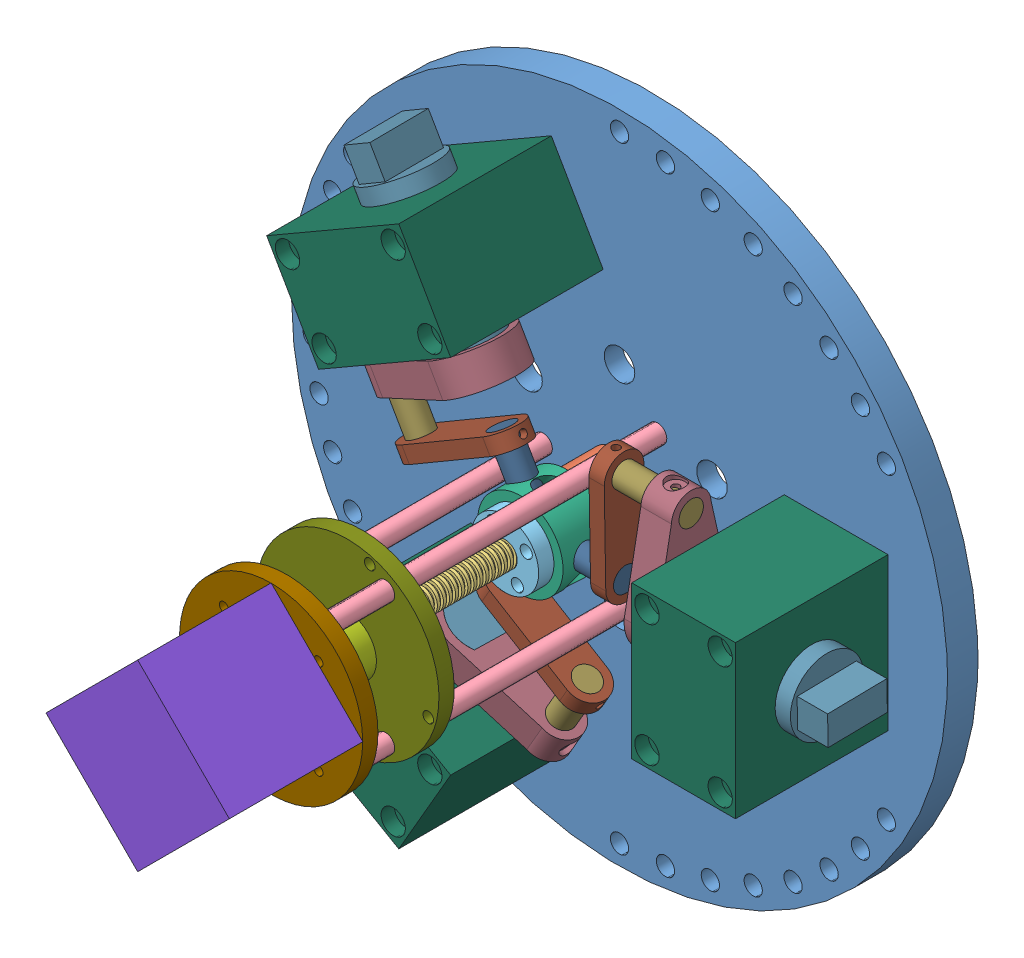
SolidWorks assembly Assem1, configuration Default. Lengths in mm.
Overall size (215 215 167.93).
30 component instances, 16 part files, 77 mates.
Components (placement in the parent):
- final base-1: final base [Default] at (64.558 110.2786 169.6179) size (215 215 10)
- lead screw holder-1: lead screw holder [Default] at (64.558 110.2786 179.6179) size (22 22 15)
- lead screw-1: lead screw [Default] at (64.558 110.2786 173.9381) x (0.932738 -0.360554 0) z (0 0 1) size (8 9.24 103.2)
- motor support-1: motor support [Default] at (77.058 131.9292 179.6179) size (6 6 110)
- main nut-1: main nut [Default] at (64.558 110.2786 217.1179) x (-0.5 0.866025 0) z (0 0 -1) size (22 22 17.19)
- main nut gasket-1: main nut gasket [Default] at (64.558 110.2786 197.1179) x (0.5 -0.866025 0) z (0 0 1) size (28 28 15)
- coupler-1: coupler [Default] at (64.558 110.2786 288.9381) x (0.864359 0.502875 0) z (0 0 -1) size (19 19 25)
- motor block-1: motor block [Default] at (64.558 110.2786 337.5481) x (0.707107 -0.707107 0) z (0 0 -1) size (42.5 42.5 58.61)
- motor holder-1: motor holder [Default] at (64.558 110.2786 293.7981) x (-1 0 0) z (0 0 -1) size (60 60 5)
- pin2-1: pin2 [Default] at (61.058 116.3407 204.6179) x (-0.865226 -0.499538 0.042959) z (-0.5 0.866025 0) size (8 8 20)
- cranck-1: cranck [Default] at (38.0694 126.1623 204.8677) x (0.865905 0.499931 -0.016654) z (0.5 -0.866025 0) size (43 13 5)
- pin-1: pin [Default] at (27.5808 114.3332 205.1175) x (-0.107928 -0.062312 0.992204) z (-0.5 0.866025 0) size (8 8 27)
- rotor-1: rotor [Default] at (27.0694 145.2149 204.8677) x (-0.865905 -0.499931 0.016654) z (0.5 -0.866025 0) size (49 25 10)
- shaft-1: shaft [Default] at (20.558 186.4888 204.6179) x (0.014423 0.008327 0.999861) z (0.5 -0.866025 0) size (24 24 64)
- shaft bracket-1: shaft bracket [Default] at (20.558 186.4888 204.6179) x (0.866025 0.5 0) z (0.5 -0.866025 0) size (50 50 34)
- motor support-4: motor support [Default] at (39.558 110.2786 179.6179) size (6 6 110)
- motor support-5: motor support [Default] at (77.058 88.6279 179.6179) size (6 6 110)
- pin2-4: pin2 [Default] at (61.058 104.2164 204.6179) x (-0.766894 0.442767 0.464576) z (-0.5 -0.866025 0) size (8 8 20)
- pin2-5: pin2 [Default] at (71.558 110.2786 204.6179) x (0 0 -1) z (1 0 0) size (8 8 20)
- cranck-4: cranck [Default] at (64.0465 79.3969 204.8677) x (0.865905 -0.499931 0.016654) z (0.5 0.866025 0) size (43 13 5)
- cranck-5: cranck [Default] at (91.558 125.2765 204.8677) x (0 0.999861 0.016654) z (-1 0 0) size (43 13 5)
- pin-4: pin [Default] at (86.558 140.2744 205.1175) x (0 0 -1) z (1 0 0) size (8 8 27)
- pin-5: pin [Default] at (79.5351 76.2281 205.1175) x (0.75 -0.433013 0.5) z (-0.5 -0.866025 0) size (8 8 27)
- rotor-4: rotor [Default] at (53.0465 60.3444 204.8677) x (0.865905 -0.499931 0.016654) z (0.5 0.866025 0) size (49 25 10)
- rotor-5: rotor [Default] at (113.558 125.2765 204.8677) x (0 0.999861 0.016654) z (-1 0 0) size (49 25 10)
- shaft-4: shaft [Default] at (152.558 110.2786 204.6179) x (0 -0.016654 0.999861) z (-1 0 0) size (24 24 64)
- shaft-5: shaft [Default] at (20.558 34.0683 204.6179) x (-0.014423 0.008327 0.999861) z (0.5 0.866025 0) size (24 24 64)
- shaft bracket-4: shaft bracket [Default] at (37.558 63.5132 204.6179) x (0.866025 -0.5 0) z (-0.5 -0.866025 0) size (50 50 34)
- shaft bracket-5: shaft bracket [Default] at (152.558 110.2786 204.6179) x (0 -1 0) z (-1 0 0) size (50 50 34)
- motor holder1-1: motor holder1 [Default] at (64.558 110.2786 263.7981) x (0.963841 -0.266478 0) z (0 0 1) size (60 60 5)
Mates (geometry in assembly coordinates):
- Coincident1: coincident: line of assembly; line of assembly; axis of final base-1 through (64.558 110.2786 179.6179) axis (0 0 -1); axis of lead screw holder-1 through (64.558 110.2786 194.6179) axis (0 0 -1)
- Coincident2: coincident: line of assembly; line of assembly; axis of final base-1 through (64.558 118.2786 175.6179) axis (0 0 1); axis of lead screw holder-1 through (64.558 118.2786 184.6179) axis (0 0 -1)
- Coincident3: coincident: line of assembly; line of assembly; axis of final base-1 through (64.558 102.2786 175.6179) axis (0 0 1); axis of lead screw holder-1 through (64.558 102.2786 184.6179) axis (0 0 -1)
- Coincident4: coincident: plane of final base-1 through (64.558 110.2786 179.6179) normal (0 0 1); plane of lead screw holder-1 through (64.558 110.2786 179.6179) normal (0 0 -1)
- Coincident5: coincident: line of assembly; line of assembly; axis of lead screw holder-1 through (64.558 110.2786 194.6179) axis (0 0 -1); axis of lead screw-1 through (64.558 110.2786 289.7579) axis (0 0 -1)
- Coincident6: coincident anti-aligned: line of final base-1 through (77.058 131.9292 173.6179) axis (0 0 1); line of motor support-1 through (77.058 131.9292 289.6179) axis (0 0 -1)
- Coincident7: coincident anti-aligned: plane of final base-1 through (64.558 110.2786 179.6179) normal (0 0 1); plane of motor support-1 through (77.058 131.9292 179.6179) normal (0 0 -1)
- Coincident8: coincident aligned: line of lead screw-1 through (64.558 110.2786 273.9381) axis (0 0 -1); line of main nut-1 through (64.558 110.2786 217.1179) axis (0 0 -1)
- RackPinionMate1: rack pinion = 0.6366 mm: cylinder of main nut-1 through (64.558 110.2786 202.1179) axis (0 0 1) radius 5.1; cylinder of lead screw-1 through (64.558 110.2786 273.9381) axis (0 0 -1) radius 4
- Coincident9: coincident aligned: line of lead screw-1 through (64.558 110.2786 273.9381) axis (0 0 -1); line of main nut gasket-1 through (64.558 110.2786 212.1179) axis (0 0 -1)
- Coincident10: coincident anti-aligned: line of main nut-1 through (60.558 117.2068 217.1179) axis (0 0 -1); line of main nut gasket-1 through (60.558 117.2068 205.6179) axis (0 0 1)
- Coincident11: coincident anti-aligned: line of main nut-1 through (57.6298 106.2786 217.1179) axis (0 0 -1); line of main nut gasket-1 through (57.6298 106.2786 205.6179) axis (0 0 1)
- Coincident12: coincident anti-aligned: plane of main nut-1 through (64.558 110.2786 212.1179) normal (0 0 -1); plane of main nut gasket-1 through (64.558 110.2786 212.1179) normal (0 0 1)
- Coincident13: coincident anti-aligned: line of lead screw-1 through (64.558 110.2786 273.9381) axis (0 0 -1); line of coupler-1 through (64.558 110.2786 263.9381) axis (0 0 1)
- Coincident14: coincident anti-aligned: plane of lead screw-1 through (64.558 110.2786 273.9381) normal (0 0 1); plane of coupler-1 through (64.558 110.2786 273.9381) normal (0 0 -1)
- Coincident15: coincident aligned: line of coupler-1 through (64.558 110.2786 263.9381) axis (0 0 1); line of motor block-1 through (64.558 110.2786 278.9381) axis (0 0 1)
- Coincident16: coincident anti-aligned: plane of coupler-1 through (64.558 110.2786 278.9381) normal (0 0 1); plane of motor block-1 through (64.558 110.2786 278.9381) normal (0 0 -1)
- Coincident17: coincident: line of coupler-1 through (64.558 110.2786 263.9381) axis (0 0 1); line of motor block-1 through (64.558 110.2786 304.6179) axis (0 0 1)
- Coincident18: coincident: line of assembly; line of assembly; axis of motor support-4 through (39.558 110.2786 289.6179) axis (0 0 -1); axis of motor holder-1 through (39.558 110.2786 309.6179) axis (0 0 -1)
- Coincident19: coincident: line of assembly; line of assembly; axis of motor support-1 through (77.058 131.9292 289.6179) axis (0 0 -1); axis of motor holder-1 through (77.058 131.9292 309.6179) axis (0 0 -1)
- Coincident21: coincident: plane of motor support-1 through (77.058 131.9292 289.6179) normal (0 0 1); plane of motor holder-1 through (64.558 110.2786 304.6179) normal (0 0 -1)
- Coincident22: coincident: plane of motor block-1 through (64.558 110.2786 293.7981) normal (0 0 -1); plane of motor holder-1 through (64.558 110.2786 309.6179) normal (0 0 1)
- Coincident23: coincident: line of assembly; line of assembly; axis of main nut gasket-1 through (61.058 116.3407 204.6179) axis (-0.5 0.866025 0); axis of pin2-1 through (51.058 133.6613 204.6179) axis (0.5 -0.866025 0)
- Coincident24: coincident: plane of main nut gasket-1 through (61.058 116.3407 204.6179) normal (-0.5 0.866025 0); plane of pin2-1 through (61.058 116.3407 204.6179) normal (0.5 -0.866025 0)
- Coincident25: coincident anti-aligned: line of pin2-1 through (51.058 133.6613 204.6179) axis (0.5 -0.866025 0); line of cranck-1 through (53.558 129.3311 204.6179) axis (-0.5 0.866025 0)
- Coincident27: coincident aligned: plane of pin2-1 through (51.058 133.6613 204.6179) normal (-0.5 0.866025 0); plane of cranck-1 through (25.0808 118.6633 205.1175) normal (-0.5 0.866025 0)
- Coincident28: coincident anti-aligned: line of cranck-1 through (27.5808 114.3332 205.1175) axis (-0.5 0.866025 0); line of pin-1 through (14.0808 137.7159 205.1175) axis (0.5 -0.866025 0)
- Coincident29: coincident aligned: plane of cranck-1 through (27.5808 114.3332 205.1175) normal (0.5 -0.866025 0); plane of pin-1 through (27.5808 114.3332 205.1175) normal (0.5 -0.866025 0)
- Coincident30: coincident anti-aligned: line of pin-1 through (14.0808 137.7159 205.1175) axis (0.5 -0.866025 0); line of rotor-1 through (19.0808 129.0556 205.1175) axis (-0.5 0.866025 0)
- Coincident31: coincident aligned: plane of pin-1 through (14.0808 137.7159 205.1175) normal (-0.5 0.866025 0); plane of rotor-1 through (14.0808 137.7159 205.1175) normal (-0.5 0.866025 0)
- Coincident32: coincident aligned: line of rotor-1 through (45.058 144.0536 204.6179) axis (-0.5 0.866025 0); line of shaft-1 through (45.058 144.0536 204.6179) axis (-0.5 0.866025 0)
- Coincident33: coincident anti-aligned: plane of rotor-1 through (39.9779 141.1206 212.7167) normal (0.865905 0.499931 -0.016654); plane of shaft-1 through (34.8625 149.7142 204.7178) normal (-0.865905 -0.499931 0.016654)
- Coincident34: coincident aligned: plane of rotor-1 through (19.0808 129.0556 205.1175) normal (0.5 -0.866025 0); plane of shaft-1 through (45.058 144.0536 204.6179) normal (0.5 -0.866025 0)
- Coincident35: coincident aligned: line of final base-1 through (40.3785 192.1587 169.6179) axis (0 0 1); line of shaft bracket-1 through (40.3785 192.1587 179.6179) axis (0 0 1)
- Coincident36: coincident aligned: line of final base-1 through (52.3785 171.3741 169.6179) axis (0 0 1); line of shaft bracket-1 through (52.3785 171.3741 179.6179) axis (0 0 1)
- Coincident37: coincident anti-aligned: plane of final base-1 through (64.558 110.2786 179.6179) normal (0 0 1); plane of shaft bracket-1 through (15.9073 144.5439 179.6179) normal (0 0 -1)
- Coincident38: coincident anti-aligned: line of shaft-1 through (45.058 144.0536 204.6179) axis (-0.5 0.866025 0); line of shaft bracket-1 through (20.558 186.4888 204.6179) axis (0.5 -0.866025 0)
- LimitDistance2: limit distance = 17.5 mm anti-aligned: plane of main nut gasket-1 through (64.558 110.2786 197.1179) normal (0 0 -1); plane of final base-1 through (64.558 110.2786 179.6179) normal (0 0 1)
- Coincident66: coincident anti-aligned: line of final base-1 through (39.558 110.2786 173.6179) axis (0 0 1); line of motor support-4 through (39.558 110.2786 289.6179) axis (0 0 -1)
- Coincident69: coincident anti-aligned: line of final base-1 through (77.058 88.6279 173.6179) axis (0 0 1); line of motor support-5 through (77.058 88.6279 289.6179) axis (0 0 -1)
- Coincident70: coincident anti-aligned: plane of final base-1 through (64.558 110.2786 179.6179) normal (0 0 1); plane of motor support-5 through (77.058 88.6279 179.6179) normal (0 0 -1)
- Coincident71: coincident: line of assembly; line of assembly; axis of main nut gasket-1 through (61.058 104.2164 204.6179) axis (-0.5 -0.866025 0); axis of pin2-4 through (51.058 86.8959 204.6179) axis (0.5 0.866025 0)
- Coincident72: coincident: plane of main nut gasket-1 through (61.058 104.2164 204.6179) normal (-0.5 -0.866025 0); plane of pin2-4 through (61.058 104.2164 204.6179) normal (0.5 0.866025 0)
- Coincident73: coincident: line of assembly; line of assembly; axis of main nut gasket-1 through (71.558 110.2786 204.6179) axis (1 0 0); axis of pin2-5 through (91.558 110.2786 204.6179) axis (-1 0 0)
- Coincident74: coincident: plane of main nut gasket-1 through (71.558 110.2786 204.6179) normal (1 0 0); plane of pin2-5 through (71.558 110.2786 204.6179) normal (-1 0 0)
- Coincident75: coincident anti-aligned: line of pin2-4 through (51.058 86.8959 204.6179) axis (0.5 0.866025 0); line of cranck-4 through (53.558 91.226 204.6179) axis (-0.5 -0.866025 0)
- Coincident76: coincident aligned: plane of pin2-4 through (51.058 86.8959 204.6179) normal (-0.5 -0.866025 0); plane of cranck-4 through (51.058 86.8959 204.6179) normal (-0.5 -0.866025 0)
- Coincident77: coincident anti-aligned: line of pin2-5 through (91.558 110.2786 204.6179) axis (-1 0 0); line of cranck-5 through (86.558 110.2786 204.6179) axis (1 0 0)
- Coincident78: coincident aligned: plane of pin2-5 through (91.558 110.2786 204.6179) normal (1 0 0); plane of cranck-5 through (91.558 110.2786 204.6179) normal (1 0 0)
- Coincident79: coincident anti-aligned: line of cranck-5 through (86.558 140.2744 205.1175) axis (1 0 0); line of pin-4 through (113.558 140.2744 205.1175) axis (-1 0 0)
- Coincident80: coincident aligned: plane of cranck-5 through (86.558 110.2786 204.6179) normal (-1 0 0); plane of pin-4 through (86.558 140.2744 205.1175) normal (-1 0 0)
- Coincident81: coincident anti-aligned: line of cranck-4 through (79.5351 76.2281 205.1175) axis (-0.5 -0.866025 0); line of pin-5 through (66.0351 52.8454 205.1175) axis (0.5 0.866025 0)
- Coincident82: coincident aligned: plane of cranck-4 through (53.558 91.226 204.6179) normal (0.5 0.866025 0); plane of pin-5 through (79.5351 76.2281 205.1175) normal (0.5 0.866025 0)
- Coincident83: coincident anti-aligned: line of pin-5 through (66.0351 52.8454 205.1175) axis (0.5 0.866025 0); line of rotor-4 through (71.0351 61.5057 205.1175) axis (-0.5 -0.866025 0)
- Coincident84: coincident aligned: plane of pin-5 through (66.0351 52.8454 205.1175) normal (-0.5 -0.866025 0); plane of rotor-4 through (66.0351 52.8454 205.1175) normal (-0.5 -0.866025 0)
- Coincident85: coincident anti-aligned: line of pin-4 through (113.558 140.2744 205.1175) axis (-1 0 0); line of rotor-5 through (103.558 140.2744 205.1175) axis (1 0 0)
- Coincident86: coincident aligned: plane of pin-4 through (113.558 140.2744 205.1175) normal (1 0 0); plane of rotor-5 through (113.558 140.2744 205.1175) normal (1 0 0)
- Coincident87: coincident aligned: line of rotor-4 through (45.058 76.5036 204.6179) axis (-0.5 -0.866025 0); line of shaft-5 through (45.058 76.5036 204.6179) axis (-0.5 -0.866025 0)
- Coincident88: coincident anti-aligned: plane of rotor-4 through (50.138 73.5706 212.7167) normal (-0.865905 0.499931 -0.016654); plane of shaft-5 through (45.2534 64.8437 204.7178) normal (0.865905 -0.499931 0.016654)
- Coincident89: coincident aligned: plane of rotor-4 through (71.0351 61.5057 205.1175) normal (0.5 0.866025 0); plane of shaft-5 through (45.058 76.5036 204.6179) normal (0.5 0.866025 0)
- Coincident90: coincident aligned: line of rotor-5 through (103.558 110.2786 204.6179) axis (1 0 0); line of shaft-4 through (103.558 110.2786 204.6179) axis (1 0 0)
- Coincident91: coincident anti-aligned: plane of rotor-5 through (103.558 116.1445 212.7167) normal (0 -0.999861 -0.016654); plane of shaft-4 through (113.558 116.2777 204.7178) normal (0 0.999861 0.016654)
- Coincident92: coincident aligned: plane of rotor-5 through (103.558 140.2744 205.1175) normal (-1 0 0); plane of shaft-4 through (103.558 110.2786 204.6179) normal (-1 0 0)
- Coincident93: coincident aligned: line of final base-1 through (147.558 90.2786 169.6179) axis (0 0 1); line of shaft bracket-5 through (147.558 90.2786 179.6179) axis (0 0 1)
- Coincident94: coincident aligned: line of final base-1 through (147.558 130.2786 169.6179) axis (0 0 1); line of shaft bracket-5 through (147.558 130.2786 179.6179) axis (0 0 1)
- Coincident95: coincident anti-aligned: plane of final base-1 through (64.558 110.2786 179.6179) normal (0 0 1); plane of shaft bracket-5 through (118.558 135.2786 179.6179) normal (0 0 -1)
- Coincident96: coincident anti-aligned: line of shaft-4 through (103.558 110.2786 204.6179) axis (1 0 0); line of shaft bracket-5 through (152.558 110.2786 204.6179) axis (-1 0 0)
- Coincident98: coincident aligned: line of final base-1 through (40.3785 28.3985 169.6179) axis (0 0 1); line of shaft bracket-4 through (40.3785 28.3985 179.6179) axis (0 0 1)
- Coincident99: coincident aligned: line of final base-1 through (52.3785 49.1831 169.6179) axis (0 0 1); line of shaft bracket-4 through (52.3785 49.1831 179.6179) axis (0 0 1)
- Coincident100: coincident anti-aligned: plane of final base-1 through (64.558 110.2786 179.6179) normal (0 0 1); plane of shaft bracket-4 through (-1.0927 46.5683 179.6179) normal (0 0 -1)
- Coincident101: coincident aligned: line of shaft-5 through (45.058 76.5036 204.6179) axis (-0.5 -0.866025 0); line of shaft bracket-4 through (37.558 63.5132 204.6179) axis (-0.5 -0.866025 0)
- Coincident102: coincident: line of assembly; line of assembly; axis of motor holder-1 through (39.558 110.2786 309.6179) axis (0 0 -1); axis of motor support-4 through (39.558 110.2786 304.6179) axis (0 0 -1)
- Coincident103: coincident: line of assembly; line of assembly; axis of motor block-1 through (64.558 88.3653 298.7981) axis (0 0 -1); axis of motor holder-1 through (64.558 88.3653 309.6179) axis (0 0 -1)
- Coincident106: coincident aligned: line of motor support-5 through (77.058 88.6279 289.6179) axis (0 0 -1); line of motor holder1-1 through (77.058 88.6279 268.7981) axis (0 0 -1)
- Coincident107: coincident aligned: line of motor support-4 through (39.558 110.2786 289.6179) axis (0 0 -1); line of motor holder1-1 through (39.558 110.2786 268.7981) axis (0 0 -1)
- Distance1: distance = 20 mm anti-aligned: plane of motor holder1-1 through (64.558 110.2786 268.7981) normal (0 0 1); plane of motor holder-1 through (64.558 110.2786 288.7981) normal (0 0 -1)
- Coincident108: coincident anti-aligned: plane of motor block-1 through (64.558 110.2786 293.7981) normal (0 0 -1); plane of motor holder-1 through (64.558 110.2786 293.7981) normal (0 0 1)
